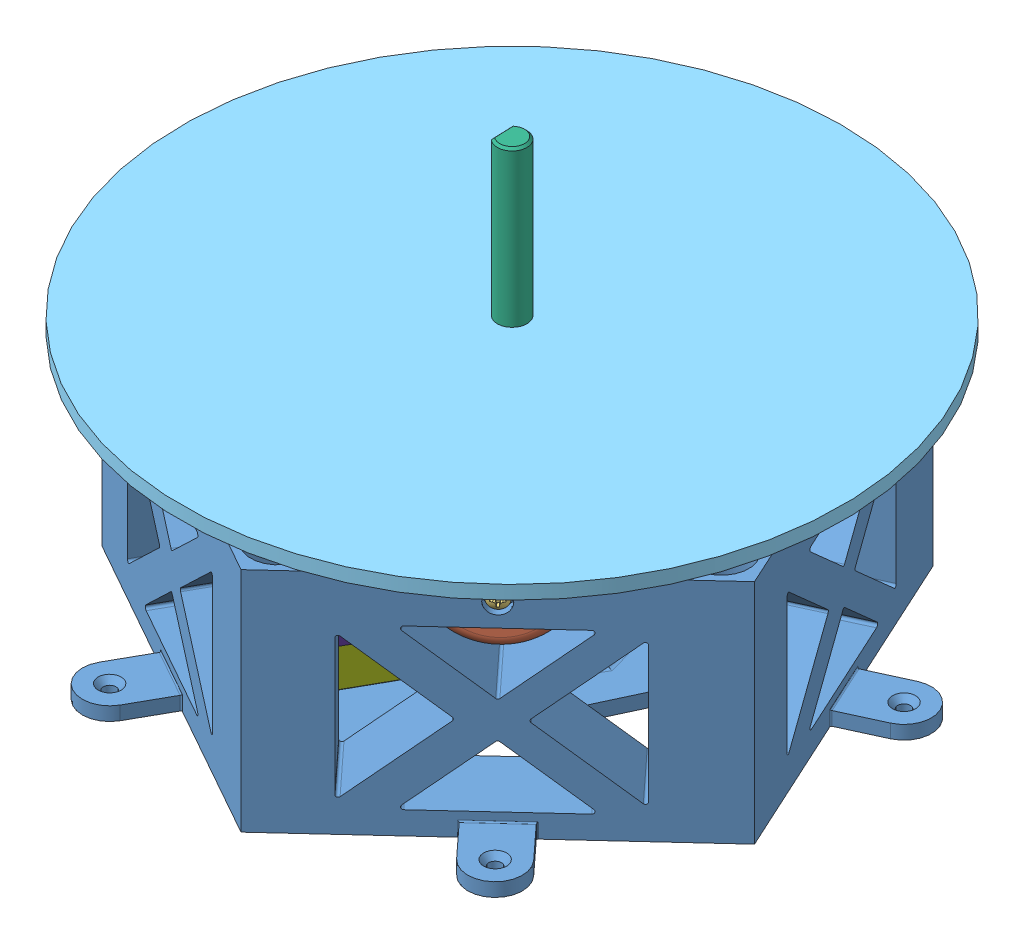
SolidWorks assembly assemblague_base_moteur, configuration Défaut. Lengths in mm.
Overall size (162.91 94.8 160.29).
50 component instances, 24 part files, 31 mates.
Components (placement in the parent):
- pentagonemagique-1: pentagonemagique [Défaut] x (0 1 0) z (-0.980522 0 -0.196409) size (50 135.63 138.98)
- XM430-W350-R.step-1: XM430-W350-R.step [Défaut] at (-5.1223 22.5918 10.1115) x (0.871838 0 0.489794) z (0 1 0) size (28.5 46.5 41)
  - Part 1.step-1: Part 1.step [Défaut] at (-0.4867 -0.6755 -0.5918) size (19.5 19.5 4)
  - Part 2.step-1: Part 2.step [Défaut] at (-0.4867 -0.6755 -0.5918) size (13.3 5.9 0.1)
  - Part 3.step-1: Part 3.step [Défaut] at (-0.4867 -0.6755 -0.5918) size (13.3 1.9 0.1)
  - Part 4.step-1: Part 4.step [Défaut] at (-0.4867 -0.6755 -0.5918) size (28.5 46.5 8.5)
  - Part 5.step-1: Part 5.step [Défaut] at (-0.4867 -0.6755 -0.5918) size (8 1.5 3)
  - Part 6.step-1: Part 6.step [Défaut] at (-0.4867 -0.6755 -0.5918) size (28.5 46.5 8.5)
  - Part 7.step-1: Part 7.step [Défaut] at (-0.4867 -0.6755 -0.5918) size (4 4 3.8)
  - Part 8.step-1: Part 8.step [Défaut] at (-0.4867 -0.6755 -0.5918) size (4 4 3.8)
  - Part 9.step-1: Part 9.step [Défaut] at (-0.4867 -0.6755 -0.5918) size (4 4 3.8)
  - Part 10.step-1: Part 10.step [Défaut] at (-0.4867 -0.6755 -0.5918) size (4 4 3.8)
  - Part 11.step-1: Part 11.step [Défaut] at (-0.4867 -0.6755 -0.5918) size (4 4 3.8)
  - Part 12.step-1: Part 12.step [Défaut] at (-0.4867 -0.6755 -0.5918) size (4 4 3.8)
  - Part 13.step-1: Part 13.step [Défaut] at (-0.4867 -0.6755 -0.5918) size (4 4 3.8)
  - Part 14.step-1: Part 14.step [Défaut] at (-0.4867 -0.6755 -0.5918) size (4 4 3.8)
  - Part 15.step-1: Part 15.step [Défaut] at (-0.4867 -0.6755 -0.5918) size (19.5 19.5 2)
  - Part 16.step-1: Part 16.step [Défaut] at (-0.4867 -0.6755 -0.5918) size (28.5 46.5 17)
- assemblage_roue-1: assemblage_roue [Défaut] at (-25.4905 41.4109 56.9227) x (0.523734 -0.799457 0.294231) z (0.489794 0 -0.871838) size (36.7 36.7 6.67)
  - 57155K337_STAINLESS STEEL BALL BEARING-1: 57155K337_STAINLESS STEEL BALL BEARING [57155K337] at (-6.2675 2.207 13.8938) size (13.89 13.89 5.56)
  - spacer-1: spacer [Défaut] at (-6.2675 2.207 11.1125) x (1 0 0) z (0 -1 0) size (6.5 6 6.5)
  - wheel-1: wheel [Défaut] at (-6.1618 2.0878 12.7826) x (0.748328 0.663329 0) z (0.663329 -0.748328 0) size (26 5 26)
- assemblage_roue-2: assemblage_roue [Défaut] at (-0.9925 42.6337 -62.42) x (0.993226 0 -0.116202) z (0.116202 0 0.993226) size (36.7 36.7 6.67)
  - 57155K337_STAINLESS STEEL BALL BEARING-1: 57155K337_STAINLESS STEEL BALL BEARING [57155K337] at (-6.2675 2.207 13.8938) size (13.89 13.89 5.56)
  - spacer-1: spacer [Défaut] at (-6.2675 2.207 11.1125) x (1 0 0) z (0 -1 0) size (6.5 6 6.5)
  - wheel-1: wheel [Défaut] at (-6.1618 2.0878 12.7826) x (0.748328 0.663329 0) z (0.663329 -0.748328 0) size (26 5 26)
- 91802A084_STAINLESS STEEL PHILLIPS OVAL HEAD SCREWS-3: 91802A084_STAINLESS STEEL PHILLIPS OVAL HEAD SCREWS [91802A084] at (-25.864 45 46.0383) x (0.871838 0 0.489794) z (-0.489794 0 0.871838) size (4.11 4.11 20.01)
- assemblage_roue-3: assemblage_roue [Défaut] at (-59.6717 42.6337 -18.3449) x (0.196409 0 -0.980522) z (0.980522 0 0.196409) size (36.7 36.7 6.67)
  - 57155K337_STAINLESS STEEL BALL BEARING-1: 57155K337_STAINLESS STEEL BALL BEARING [57155K337] at (-6.2675 2.207 13.8938) size (13.89 13.89 5.56)
  - spacer-1: spacer [Défaut] at (-6.2675 2.207 11.1125) x (1 0 0) z (0 -1 0) size (6.5 6 6.5)
  - wheel-1: wheel [Défaut] at (-6.1618 2.0878 12.7826) x (0.748328 0.663329 0) z (0.663329 -0.748328 0) size (26 5 26)
- assemblage_roue-4: assemblage_roue [Défaut] at (37.7153 41.9494 49.7101) x (-0.730647 -0.111532 0.673584) z (-0.677813 0 -0.735235) size (36.7 36.7 6.67)
  - 57155K337_STAINLESS STEEL BALL BEARING-1: 57155K337_STAINLESS STEEL BALL BEARING [57155K337] at (-6.2675 2.207 13.8938) size (13.89 13.89 5.56)
  - spacer-1: spacer [Défaut] at (-6.2675 2.207 11.1125) x (1 0 0) z (0 -1 0) size (6.5 6 6.5)
  - wheel-1: wheel [Défaut] at (-6.1618 2.0878 12.7826) x (0.748328 0.663329 0) z (0.663329 -0.748328 0) size (26 5 26)
- assemblage_roue-5: assemblage_roue [Défaut] at (59.0583 42.6337 -20.2328) x (0.417438 0 0.908705) z (-0.908705 0 0.417438) size (36.7 36.7 6.67)
  - 57155K337_STAINLESS STEEL BALL BEARING-1: 57155K337_STAINLESS STEEL BALL BEARING [57155K337] at (-6.2675 2.207 13.8938) size (13.89 13.89 5.56)
  - spacer-1: spacer [Défaut] at (-6.2675 2.207 11.1125) x (1 0 0) z (0 -1 0) size (6.5 6 6.5)
  - wheel-1: wheel [Défaut] at (-6.1618 2.0878 12.7826) x (0.748328 0.663329 0) z (0.663329 -0.748328 0) size (26 5 26)
- 91802A084_STAINLESS STEEL PHILLIPS OVAL HEAD SCREWS-4: 91802A084_STAINLESS STEEL PHILLIPS OVAL HEAD SCREWS [91802A084] at (35.7926 45 38.8248) x (0.735235 0 -0.677813) z (0.677813 0 0.735235) size (4.11 4.11 20.01)
- 91802A084_STAINLESS STEEL PHILLIPS OVAL HEAD SCREWS-5: 91802A084_STAINLESS STEEL PHILLIPS OVAL HEAD SCREWS [91802A084] at (-6.1362 45 -52.4482) x (-0.911067 -0.39824 0.10659) z (-0.116202 0 -0.993226) size (4.11 4.11 20.01)
- 91802A084_STAINLESS STEEL PHILLIPS OVAL HEAD SCREWS-6: 91802A084_STAINLESS STEEL PHILLIPS OVAL HEAD SCREWS [91802A084] at (47.9851 45 -22.0432) x (-0.352907 -0.534115 -0.76823) z (0.908705 0 -0.417438) size (4.11 4.11 20.01)
- 91802A084_STAINLESS STEEL PHILLIPS OVAL HEAD SCREWS-7: 91802A084_STAINLESS STEEL PHILLIPS OVAL HEAD SCREWS [91802A084] at (-51.7774 45 -10.3716) x (0.122944 0.779855 -0.613767) z (-0.980522 0 -0.196409) size (4.11 4.11 20.01)
- 90480A003_LOW-STRENGTH STEEL HEX NUT-1: 90480A003_LOW-STRENGTH STEEL HEX NUT [90480A003] at (26.5745 45 28.8258) x (-0.734898 0.030273 0.677502) z (0.022258 0.999542 -0.02052) size (4.76 1.94 5.5)
- 90480A003_LOW-STRENGTH STEEL HEX NUT-2: 90480A003_LOW-STRENGTH STEEL HEX NUT [90480A003] at (35.6269 45 -16.3662) x (-0.349922 0.54527 -0.761732) z (-0.227617 -0.838261 -0.49549) size (4.76 1.94 5.5)
- 90480A003_LOW-STRENGTH STEEL HEX NUT-3: 90480A003_LOW-STRENGTH STEEL HEX NUT [90480A003] at (-19.203 45 34.1815) x (-0.543105 -0.782268 -0.305113) z (-0.682011 0.622942 -0.38315) size (4.76 1.94 5.5)
- 90480A003_LOW-STRENGTH STEEL HEX NUT-4: 90480A003_LOW-STRENGTH STEEL HEX NUT [90480A003] at (-4.5558 45 -38.9407) x (0.937229 0.331025 -0.109651) z (-0.328783 0.943622 0.038466) size (4.76 1.94 5.5)
- 90480A003_LOW-STRENGTH STEEL HEX NUT-5: 90480A003_LOW-STRENGTH STEEL HEX NUT [90480A003] at (-38.4426 45 -7.7005) x (-0.12604 0.766938 0.629222) z (-0.150633 -0.641721 0.752) size (4.76 1.94 5.5)
- plaque_tournante_2-1: plaque_tournante_2 [Default] at (0 60.7215 0) x (-0.035547 0 -0.999368) z (0.999368 0 -0.035547) size (145 3 145)
- D_shaft-1: D_shaft [Default] at (0 69.4 0) x (-0.035547 0 -0.999368) z (0.999368 0 -0.035547) size (6.5 50.8 5.5)
Mates (geometry in assembly coordinates):
- Coaxiale2: concentric anti-aligned: line of pentagonemagique-1 through (0 0 0) axis (0 1 0); circle of XM430-W350-R.step-1/Part 6.step-1
- Coïncidente1: coincident anti-aligned: plane of pentagonemagique-1 through (0 3 0) normal (0 1 0); plane of XM430-W350-R.step-1/Part 15.step-1 through (0 3 0) normal (0 -1 0)
- Parallèle1: parallel aligned: line of pentagonemagique-1 through (-44.9289 3 20.6393) axis (0.871838 0 0.489794); line of XM430-W350-R.step-1/Part 6.step-1 through (-27.9453 5.25 24.7323) axis (0.871838 0 0.489794)
- Coïncidente3: coincident: point of pentagonemagique-1
- Coïncidente4: coincident aligned: plane of pentagonemagique-1 through (0 0 0) normal (0 1 0)
- Coïncidente11: coincident anti-aligned: plane of pentagonemagique-1 through (-46.7754 40 32.2189) normal (0.489794 0 -0.871838); plane of assemblage_roue-1/spacer-1 through (-24.8685 45.0957 44.5261) normal (-0.489794 0 0.871838)
- Coïncidente12: coincident anti-aligned: circle of pentagonemagique-1; circle of assemblage_roue-1/spacer-1
- Coïncidente13: coincident anti-aligned: cone of pentagonemagique-1; cone of 91802A084_STAINLESS STEEL PHILLIPS OVAL HEAD SCREWS-3 through (-26.4985 45 47.1676) axis (0.489794 0 -0.871838)
- Coïncidente14: coincident anti-aligned: circle of pentagonemagique-1; circle of assemblage_roue-3/spacer-1
- Coïncidente15: coincident anti-aligned: circle of pentagonemagique-1; circle of assemblage_roue-2/spacer-1
- Coïncidente16: coincident anti-aligned: circle of pentagonemagique-1; circle of assemblage_roue-5/spacer-1
- Coïncidente18: coincident anti-aligned: circle of pentagonemagique-1; circle of assemblage_roue-4/spacer-1
- Coïncidente19: coincident anti-aligned: circle of pentagonemagique-1; cone of 91802A084_STAINLESS STEEL PHILLIPS OVAL HEAD SCREWS-4 through (36.6706 45 39.7772) axis (-0.677813 0 -0.735235)
- Coïncidente20: coincident anti-aligned: circle of pentagonemagique-1; cone of 91802A084_STAINLESS STEEL PHILLIPS OVAL HEAD SCREWS-6 through (49.1622 45 -22.584) axis (-0.908705 0 0.417438)
- Coïncidente21: coincident anti-aligned: circle of pentagonemagique-1; cone of 91802A084_STAINLESS STEEL PHILLIPS OVAL HEAD SCREWS-5 through (-6.2867 45 -53.7349) axis (0.116202 0 0.993226)
- Coïncidente22: coincident anti-aligned: circle of pentagonemagique-1; cone of 91802A084_STAINLESS STEEL PHILLIPS OVAL HEAD SCREWS-7 through (-53.0476 45 -10.626) axis (0.980522 0 0.196409)
- Coaxiale16: concentric aligned: circle of pentagonemagique-1; circle of 90480A003_LOW-STRENGTH STEEL HEX NUT-4
- Coïncidente24: coincident anti-aligned: plane of pentagonemagique-1 through (24.2167 50 -43.1061) normal (0.116202 0 0.993226); plane of 90480A003_LOW-STRENGTH STEEL HEX NUT-4 through (-6.4278 42.9144 -39.5208) normal (-0.116202 0 -0.993226)
- Coaxiale18: concentric aligned: circle of pentagonemagique-1; circle of 90480A003_LOW-STRENGTH STEEL HEX NUT-2
- Coïncidente25: coincident anti-aligned: plane of pentagonemagique-1 through (48.4797 50 9.711) normal (-0.908705 0 0.417438); plane of 90480A003_LOW-STRENGTH STEEL HEX NUT-2 through (37.4944 44.854 -14.2024) normal (0.908705 0 -0.417438)
- Coaxiale19: concentric aligned: circle of pentagonemagique-1; circle of 90480A003_LOW-STRENGTH STEEL HEX NUT-1
- Coïncidente26: coincident anti-aligned: plane of pentagonemagique-1 through (5.7453 50 49.1078) normal (-0.677813 0 -0.735235); plane of 90480A003_LOW-STRENGTH STEEL HEX NUT-1 through (28.8319 43.5537 27.8243) normal (0.677813 0 0.735235)
- Coaxiale20: concentric aligned: circle of pentagonemagique-1; circle of 90480A003_LOW-STRENGTH STEEL HEX NUT-5
- Coïncidente28: coincident anti-aligned: plane of pentagonemagique-1 through (-33.5129 50 -36.352) normal (0.980522 0 0.196409); plane of 90480A003_LOW-STRENGTH STEEL HEX NUT-5 through (-38.7137 44.056 -10.3886) normal (-0.980522 0 -0.196409)
- Coaxiale21: concentric aligned: circle of pentagonemagique-1; circle of 90480A003_LOW-STRENGTH STEEL HEX NUT-3
- Coïncidente29: coincident anti-aligned: plane of pentagonemagique-1 through (-44.9289 50 20.6393) normal (0.489794 0 -0.871838); plane of 90480A003_LOW-STRENGTH STEEL HEX NUT-3 through (-17.3609 46.0063 36.1268) normal (-0.489794 0 0.871838)
- Concentric1: concentric anti-aligned: cylinder of XM430-W350-R.step-1/Part 1.step-1 through (0 44 0) axis (0 1 0) radius 4; cylinder of D_shaft-1 through (0 94.8 0) axis (0 -1 0) radius 3.25
- Coincident1: coincident anti-aligned: plane of XM430-W350-R.step-1/Part 1.step-1 through (0 44 0) normal (0 1 0); plane of D_shaft-1 through (0 44 0) normal (0 -1 0)
- Concentric2: concentric anti-aligned: cylinder of plaque_tournante_2-1 through (0 57.7205 0) axis (0 1 0) radius 3.25; cylinder of D_shaft-1 through (0 94.8 0) axis (0 -1 0) radius 3.25
- Coincident2: coincident anti-aligned: plane of plaque_tournante_2-1 through (-2.1652 57.7205 2.4237) normal (0.999368 0 -0.035547); plane of D_shaft-1 through (-2.1652 94.8 2.4237) normal (-0.999368 0 0.035547)
- Tangent1: tangent anti-aligned: torus of assemblage_roue-3/wheel-1; plane of plaque_tournante_2-1 through (0 57.7215 0) normal (0 -1 0)
